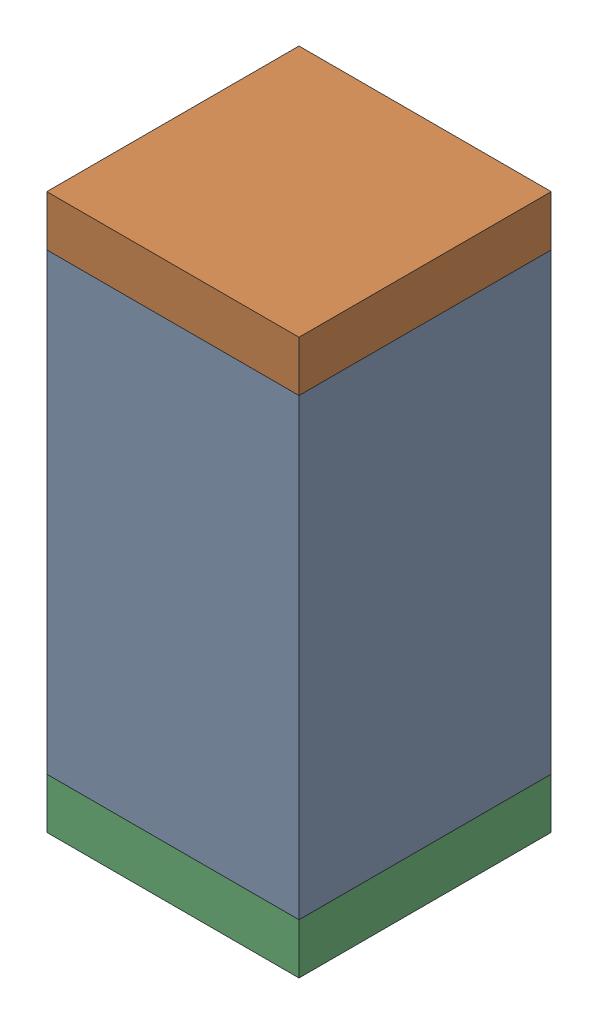
SolidWorks assembly R49, configuration Default. Lengths in mm.
Overall size (0.5 1.1 0.5).
6 component instances, 2 part files, 0 mates.
Components (placement in the parent):
- 791586336-1: 791586336 [Default] at (116.1 59.35 0) size (0.5 0.9 0.5)
  - Extruded_8-1: Extruded_8 [Default] at origin size (0.5 0.9 0.5)
- 810157360-1: 810157360 [Default] at (116.1 59.85 0) size (0.5 0.1 0.5)
  - Extruded_9-1: Extruded_9 [Default] at origin size (0.5 0.1 0.5)
- 810157360-2: 810157360 [Default] at (116.1 58.85 0) size (0.5 0.1 0.5)
  - Extruded_9-1: Extruded_9 [Default] at origin size (0.5 0.1 0.5)
